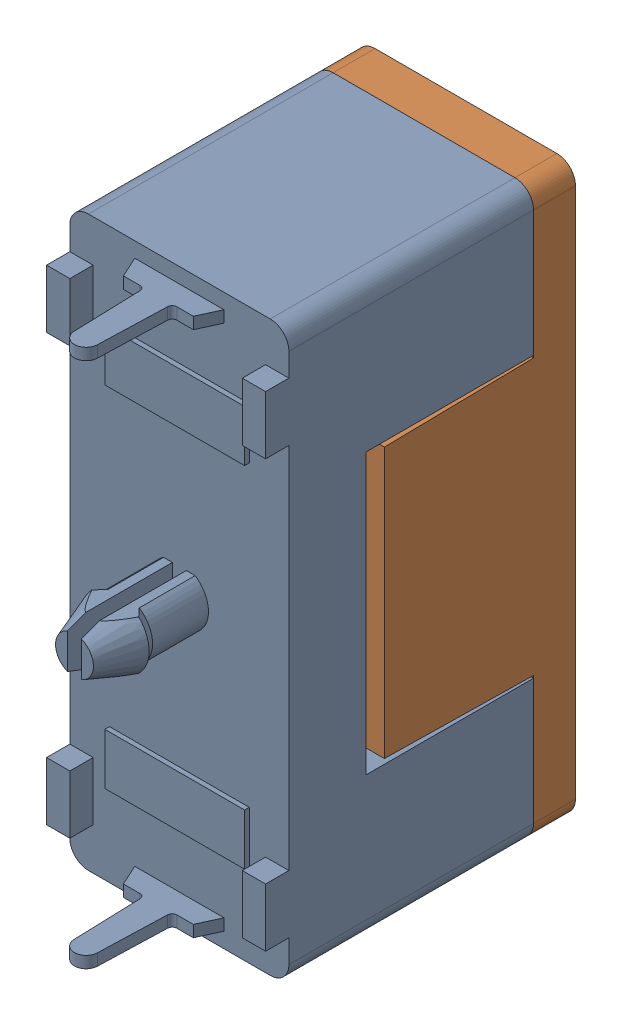
SolidWorks assembly F1, configuration Default. Lengths in mm.
Overall size (9.4 24.4 17).
2 component instances, 2 part files, 0 mates.
Components (placement in the parent):
- 696107003002-1: 696107003002 [Default] at (19.3049 14.4939 -3.1914) x (0 -1 0) z (0 0 -1) size (24.4 9.4 15)
- 696107003002_2-1: 696107003002_2 [Default] at (19.3049 14.4939 -3.1914) x (0 -1 0) z (0 0 -1) size (24.4 9.4 8.4)
